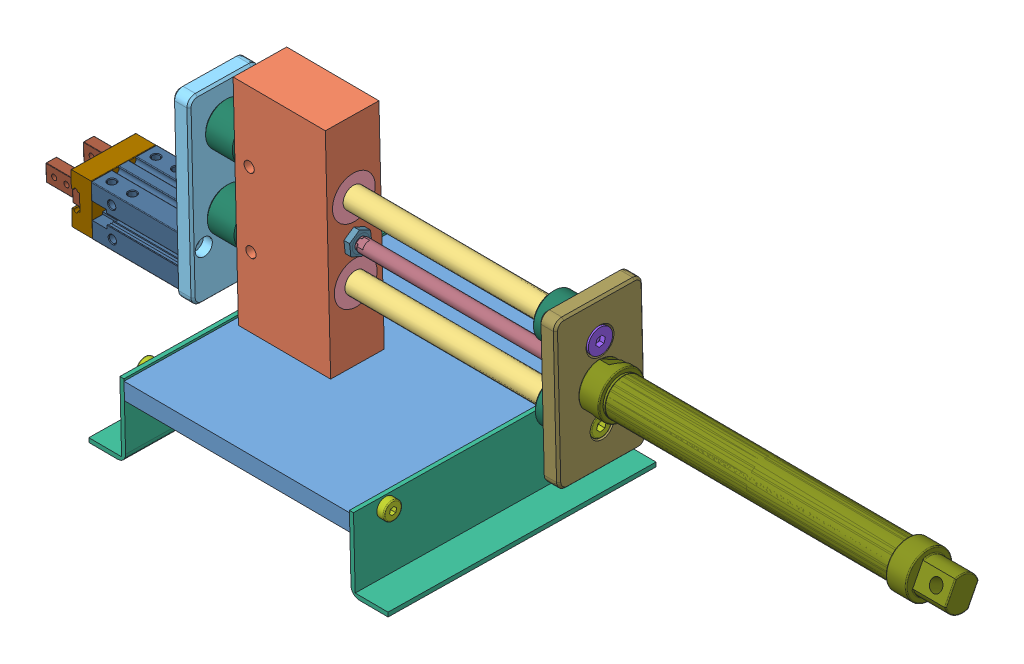
SolidWorks assembly cum s3, configuration Default. Lengths in mm.
Overall size (436.61 137.7 128.52).
35 component instances, 17 part files, 73 mates.
Components (placement in the parent):
- tam de lon-1: tam de lon [Default] at (119.0958 51.1975 54.0073) x (-0.999587 -0.017639 -0.022689) z (-0.022562 -0.007384 0.999718) size (110 8 125)
- con truot s1-2: con truot s1 [Default] at (88.5768 136.6703 53.9498) x (0.999587 0.017639 0.022689) z (0.022562 0.007384 -0.999718) size (45 102 25)
- chot dan huong-1: chot dan huong [Default] at (48.5237 118.4612 52.9114) x (0.021471 -0.983136 -0.181614) z (-0.019103 -0.182026 0.983108) size (10 175 10)
- chot dan huong-2: chot dan huong [Default] at (49.1468 83.4676 52.667) x (0.026236 -0.237789 -0.970963) z (0.011731 -0.971157 0.238153) size (10 175 10)
- bac lot-1: bac lot [Default] at (66.3976 118.7766 53.3171) x (0.028076 -0.767933 -0.639915) z (-0.006137 -0.640287 0.768111) size (20 12 20)
- bac lot-2: bac lot [Default] at (67.0207 83.783 53.0727) x (0.018145 -0.999587 -0.022287) z (-0.022287 -0.022689 0.999494) size (20 12 20)
- bac lot-3: bac lot [Default] at (111.379 119.5704 54.3381) x (-0.014484 -0.372719 0.927831) z (0.024823 -0.927776 -0.37231) size (20 12 20)
- bac lot-4: bac lot [Default] at (112.0021 84.5768 54.0937) x (-0.014484 -0.372719 0.927831) z (0.024823 -0.927776 -0.37231) size (20 12 20)
- ban canh truoc-1: ban canh truoc [Default] at (48.9776 92.9659 52.7333) x (-0.022562 -0.007384 0.999718) z (0.017801 -0.999817 -0.006983) size (33 8 86)
- khoi do-1: khoi do [Default] at (173.7917 36.5109 117.6508) x (0.022562 0.007384 -0.999718) z (-0.999587 -0.017639 -0.022689) size (125 35 18)
- khoi do-2: khoi do [Default] at (64.9414 35.4633 -9.8487) x (-0.022562 -0.007384 0.999718) z (0.999587 0.017639 0.022689) size (125 35 18)
- socket head thin cap screw_din-2: socket head thin cap screw_din [DIN 7984 - M5 x 12 --- 9.6N] at (57.6203 45.7804 100.0932) x (0.999587 0.017639 0.022689) z (-0.022689 -0.0002 0.999743) size (15.5 8.5 8.5)
- socket head thin cap screw_din-3: socket head thin cap screw_din [DIN 7984 - M5 x 12 --- 9.6N] at (59.7637 46.4818 5.12) x (0.999587 0.017639 0.022689) z (-0.022689 -0.0002 0.999743) size (15.5 8.5 8.5)
- socket head thin cap screw_din-4: socket head thin cap screw_din [DIN 7984 - M5 x 12 --- 9.6N] at (180.7137 48.6161 7.8654) x (-0.999587 -0.017639 -0.022689) z (0.022689 -0.968916 -0.246346) size (15.5 8.5 8.5)
- socket head thin cap screw_din-5: socket head thin cap screw_din [DIN 7984 - M5 x 12 --- 9.6N] at (178.5703 47.9147 102.8386) x (-0.999587 -0.017639 -0.022689) z (0.022689 -0.968916 -0.246346) size (15.5 8.5 8.5)
- socket head thin cap screw_din-6: socket head thin cap screw_din [DIN 7984 - M5 x 12 --- 9.6N] at (108.0343 45.1492 61.2151) x (-0.017801 0.999817 0.006983) z (-0.006983 -0.007108 0.99995) size (15.5 8.5 8.5)
- socket head thin cap screw_din-7: socket head thin cap screw_din [DIN 7984 - M5 x 12 --- 9.6N] at (72.3876 44.6249 45.4025) x (-0.017801 0.999817 0.006983) z (-0.006983 -0.007108 0.99995) size (15.5 8.5 8.5)
- socket head thin cap screw_din-10: socket head thin cap screw_din [DIN 7984 - M6 x 14 --- 11N] at (41.35 83.33 52.49) x (0.999587 0.017639 0.022689) z (-0.022689 -0.0002 0.999743) size (18 10 10)
- socket csink head cap screw 10642_din-2: socket csink head cap screw 10642_din [EN ISO 10642 - M6 x 16 - 16N] at (40.3071 118.3162 52.7248) x (0.999587 0.017639 0.022689) z (-0.022678 -0.000819 0.999742) size (16 11.34 11.34)
- NMHZ2-16D-1: NMHZ2-16D [Default] at (57.0123 62.7023 30.2779) x (-0.022562 -0.007384 0.999718) z (-0.999587 -0.017639 -0.022689) size (30.6 23.6 52.5)
  - NMHZ2-16D Slipway-1: NMHZ2-16D Slipway [Default] at (22.4069 2.6078 57.488) size (30.1 23.6 10)
  - NMHZ2-16D cylinder-2: NMHZ2-16D cylinder [Default] at (22.4069 2.6078 14.988) size (30.6 23.6 42.5)
- NMHZ2-16D air claw-1: NMHZ2-16D air claw [Default] at (-9.0173 63.9837 51.9473) x (-0.022562 -0.007384 0.999718) z (-0.999587 -0.017639 -0.022689) size (12 10 21)
- NMHZ2-16D air claw-2: NMHZ2-16D air claw [Default] at (-8.9618 64.0018 49.49) x (0.022562 0.007384 -0.999718) z (-0.999587 -0.017639 -0.022689) size (12 10 21)
- ban canh sau-1: ban canh sau [Default] at (223.763 104.0512 56.7598) x (-0.022562 -0.007384 0.999718) z (-0.017801 0.999817 0.006983) size (41 8 70)
- socket head thin cap screw_din-11: socket head thin cap screw_din [DIN 7984 - M6 x 14 --- 11N] at (231.8713 86.692 56.8146) x (-0.999587 -0.017639 -0.022689) z (0.022689 -0.968916 -0.246346) size (18 10 10)
- socket csink head cap screw 10642_din-6: socket csink head cap screw 10642_din [EN ISO 10642 - M6 x 16 - 16N] at (231.668 121.693 57.0685) x (-0.999587 -0.017639 -0.022689) z (0.022777 -0.96767 -0.251187) size (16 11.34 11.34)
- Part1-1: Part1 [Default] at (260.6534 104.7022 57.5972) x (0.027343 -0.826758 -0.561893) z (0.008847 0.562281 -0.826899) size (6.2 165 6.2)
- Part2-1: Part2 [Default] at (113.19 102.1 54.2499) x (0.02801 -0.421298 -0.90649) z (-0.00643 0.906751 -0.421618) size (11.32 3 9.8)
- bac chan-1: bac chan [Default] at (48.5237 118.4612 52.9114) x (-0.000114 0.791927 -0.610616) z (0.028739 -0.610361 -0.791602) size (20 15 20)
- bac chan-2: bac chan [Default] at (49.1468 83.4676 52.667) x (0.014063 0.388293 -0.921429) z (0.025063 -0.921367 -0.387885) size (20 15 20)
- bac chan-3: bac chan [Default] at (208.4576 121.2834 56.5416) x (0.028616 -0.683831 -0.729079) z (-0.002656 -0.729428 0.684053) size (20 15 20)
- bac chan-4: bac chan [Default] at (209.0807 86.2898 56.2973) x (-0.005838 -0.648408 0.76127) z (-0.02814 0.761088 0.648038) size (20 15 20)
- 16 X 100 Cylinder bore-1: 16 X 100 Cylinder bore [Default] at (311.9265 105.6069 58.761) x (0.028286 -0.464271 -0.885241) z (0.999587 0.017639 0.022689) size (21.5 21.5 192)
- hex thin nut chamfered gradeab_din-2: hex thin nut chamfered gradeab_din [Hexagon Thin Nut ISO 4035 - M8 - N] at (219.7646 103.9806 56.669) x (0.019005 -0.997928 -0.061469) z (-0.999587 -0.017639 -0.022689) size (13 15.01 4)
Mates (geometry in assembly coordinates):
- Parallel5: parallel anti-aligned: plane of tam de lon-1 through (119.0958 51.1975 54.0073) normal (-0.017801 0.999817 0.006983); plane of con truot s1-2 through (90.1077 50.686 53.3493) normal (0.017801 -0.999817 -0.006983)
- Parallel6: parallel anti-aligned: plane of tam de lon-1 through (172.8053 43.7076 117.6817) normal (-0.022562 -0.007384 0.999718); plane of con truot s1-2 through (67.6142 66.3785 40.454) normal (0.022562 0.007384 -0.999718)
- Concentric3: concentric aligned: cylinder of tam de lon-1 through (72.2844 50.4239 45.443) axis (0.017801 -0.999817 -0.006983) radius 2.75; circle of con truot s1-2
- Coincident1: coincident anti-aligned: plane of tam de lon-1 through (119.0958 51.1975 54.0073) normal (-0.017801 0.999817 0.006983); plane of con truot s1-2 through (90.1077 50.686 53.3493) normal (0.017801 -0.999817 -0.006983)
- Concentric4: concentric anti-aligned: cylinder of con truot s1-2 through (41.408 118.3356 52.7498) axis (0.999587 0.017639 0.022689) radius 6; cylinder of chot dan huong-1 through (321.411 123.2766 59.1055) axis (-0.999587 -0.017639 -0.022689) radius 5
- Concentric5: concentric anti-aligned: cylinder of con truot s1-2 through (42.031 83.342 52.5054) axis (0.999587 0.017639 0.022689) radius 6; cylinder of chot dan huong-2 through (322.034 88.283 58.8611) axis (-0.999587 -0.017639 -0.022689) radius 5
- Concentric6: concentric anti-aligned: cylinder of con truot s1-2 through (41.408 118.3356 52.7498) axis (0.999587 0.017639 0.022689) radius 6; cylinder of bac lot-1 through (78.3927 118.9883 53.5893) axis (-0.999587 -0.017639 -0.022689) radius 6
- Coincident2: coincident anti-aligned: plane of con truot s1-2 through (68.3968 118.8119 53.3624) normal (-0.999587 -0.017639 -0.022689); plane of bac lot-1 through (68.3968 118.8119 53.3624) normal (0.999587 0.017639 0.022689)
- Concentric7: concentric anti-aligned: cylinder of con truot s1-2 through (42.031 83.342 52.5054) axis (0.999587 0.017639 0.022689) radius 6; cylinder of bac lot-2 through (79.0157 83.9947 53.3449) axis (-0.999587 -0.017639 -0.022689) radius 6
- Coincident3: coincident anti-aligned: plane of con truot s1-2 through (69.0199 83.8183 53.1181) normal (-0.999587 -0.017639 -0.022689); plane of bac lot-2 through (69.0199 83.8183 53.1181) normal (0.999587 0.017639 0.022689)
- Concentric8: concentric aligned: cylinder of con truot s1-2 through (41.408 118.3356 52.7498) axis (0.999587 0.017639 0.022689) radius 6; cylinder of bac lot-3 through (99.384 119.3587 54.0658) axis (0.999587 0.017639 0.022689) radius 6
- Coincident4: coincident anti-aligned: plane of con truot s1-2 through (109.3799 119.5351 54.2927) normal (0.999587 0.017639 0.022689); plane of bac lot-3 through (109.3799 119.5351 54.2927) normal (-0.999587 -0.017639 -0.022689)
- Concentric9: concentric aligned: cylinder of con truot s1-2 through (42.031 83.342 52.5054) axis (0.999587 0.017639 0.022689) radius 6; cylinder of bac lot-4 through (100.0071 84.3651 53.8214) axis (0.999587 0.017639 0.022689) radius 6
- Coincident5: coincident anti-aligned: plane of con truot s1-2 through (110.0029 84.5415 54.0483) normal (0.999587 0.017639 0.022689); plane of bac lot-4 through (110.0029 84.5415 54.0483) normal (-0.999587 -0.017639 -0.022689)
- Concentric10: concentric aligned: cylinder of chot dan huong-1 through (321.411 123.2766 59.1055) axis (-0.999587 -0.017639 -0.022689) radius 5; cylinder of ban canh truoc-1 through (48.5237 118.4612 52.9114) axis (-0.999587 -0.017639 -0.022689) radius 3.3
- Concentric11: concentric aligned: cylinder of chot dan huong-2 through (322.034 88.283 58.8611) axis (-0.999587 -0.017639 -0.022689) radius 5; cylinder of ban canh truoc-1 through (49.1468 83.4676 52.667) axis (-0.999587 -0.017639 -0.022689) radius 3.3
- Coincident6: coincident anti-aligned: plane of chot dan huong-1 through (48.5237 118.4612 52.9114) normal (-0.999587 -0.017639 -0.022689); plane of ban canh truoc-1 through (48.9776 92.9659 52.7333) normal (0.999587 0.017639 0.022689)
- Coincident7: coincident anti-aligned: plane of chot dan huong-2 through (49.1468 83.4676 52.667) normal (-0.999587 -0.017639 -0.022689); plane of ban canh truoc-1 through (48.9776 92.9659 52.7333) normal (0.999587 0.017639 0.022689)
- Parallel7: parallel aligned: plane of tam de lon-1 through (65.671 42.6903 -9.7789) normal (-0.999587 -0.017639 -0.022689); plane of khoi do-1 through (176.0884 18.6354 -7.4646) normal (-0.999587 -0.017639 -0.022689)
- Parallel8: parallel aligned: plane of tam de lon-1 through (119.0958 51.1975 54.0073) normal (-0.017801 0.999817 0.006983); plane of khoi do-1 through (175.4654 53.629 -7.2202) normal (-0.017801 0.999817 0.006983)
- Concentric14: concentric aligned: cylinder of tam de lon-1 through (160.2221 48.2545 7.4003) axis (0.999587 0.017639 0.022689) radius 2.5; cylinder of khoi do-1 through (52.2667 46.3495 4.9498) axis (0.999587 0.017639 0.022689) radius 2.5
- Coincident10: coincident anti-aligned: plane of tam de lon-1 through (175.6256 44.6306 -7.2831) normal (0.999587 0.017639 0.022689); plane of khoi do-1 through (176.0884 18.6354 -7.4646) normal (-0.999587 -0.017639 -0.022689)
- Parallel9: parallel anti-aligned: plane of tam de lon-1 through (65.671 42.6903 -9.7789) normal (-0.999587 -0.017639 -0.022689); plane of khoi do-2 through (63.3136 15.7721 115.0043) normal (0.999587 0.017639 0.022689)
- Parallel10: parallel anti-aligned: plane of tam de lon-1 through (119.0958 51.1975 54.0073) normal (-0.017801 0.999817 0.006983); plane of khoi do-2 through (63.3136 15.7721 115.0043) normal (0.017801 -0.999817 -0.006983)
- Concentric15: concentric aligned: cylinder of tam de lon-1 through (80.2552 46.8434 5.5851) axis (-0.999587 -0.017639 -0.022689) radius 2.5; cylinder of khoi do-2 through (188.2106 48.7484 8.0356) axis (-0.999587 -0.017639 -0.022689) radius 2.5
- Coincident11: coincident anti-aligned: plane of tam de lon-1 through (65.671 42.6903 -9.7789) normal (-0.999587 -0.017639 -0.022689); plane of khoi do-2 through (63.3136 15.7721 115.0043) normal (0.999587 0.017639 0.022689)
- Concentric16: concentric aligned: cylinder of khoi do-2 through (186.0672 48.047 103.0088) axis (-0.999587 -0.017639 -0.022689) radius 2.5; cylinder of socket head thin cap screw_din-2 through (25.8834 45.2204 99.3728) axis (-0.999587 -0.017639 -0.022689) radius 4.25
- Coincident12: coincident anti-aligned: plane of khoi do-2 through (61.2788 17.7365 114.9729) normal (-0.999587 -0.017639 -0.022689); plane of socket head thin cap screw_din-2 through (61.0438 50.0915 100.1718) normal (0.999587 0.017639 0.022689)
- Concentric17: concentric aligned: cylinder of khoi do-2 through (188.2106 48.7484 8.0356) axis (-0.999587 -0.017639 -0.022689) radius 2.5; cylinder of socket head thin cap screw_din-3 through (28.0268 45.9218 4.3996) axis (-0.999587 -0.017639 -0.022689) radius 4.25
- Coincident13: coincident anti-aligned: plane of khoi do-2 through (61.2788 17.7365 114.9729) normal (-0.999587 -0.017639 -0.022689); plane of socket head thin cap screw_din-3 through (63.1872 50.7929 5.1986) normal (0.999587 0.017639 0.022689)
- Concentric18: concentric aligned: cylinder of khoi do-1 through (52.2667 46.3495 4.9498) axis (0.999587 0.017639 0.022689) radius 2.5; cylinder of socket head thin cap screw_din-4 through (212.4506 49.1762 8.5858) axis (0.999587 0.017639 0.022689) radius 4.25
- Coincident14: coincident anti-aligned: plane of khoi do-1 through (178.052 20.6703 -7.4053) normal (0.999587 0.017639 0.022689); plane of socket head thin cap screw_din-4 through (177.2901 49.6031 3.6681) normal (-0.999587 -0.017639 -0.022689)
- Concentric19: concentric aligned: cylinder of khoi do-1 through (50.1234 45.6481 99.9231) axis (0.999587 0.017639 0.022689) radius 2.5; cylinder of socket head thin cap screw_din-5 through (210.3072 48.4747 103.559) axis (0.999587 0.017639 0.022689) radius 4.25
- Coincident15: coincident anti-aligned: plane of khoi do-1 through (178.052 20.6703 -7.4053) normal (0.999587 0.017639 0.022689); plane of socket head thin cap screw_din-5 through (175.1467 48.9017 98.6413) normal (-0.999587 -0.017639 -0.022689)
- Concentric20: concentric aligned: cylinder of tam de lon-1 through (107.972 48.6485 61.2395) axis (0.017801 -0.999817 -0.006983) radius 5; cylinder of socket head thin cap screw_din-6 through (108.5995 13.405 60.9934) axis (0.017801 -0.999817 -0.006983) radius 4.25
- Coincident16: coincident anti-aligned: plane of tam de lon-1 through (107.972 48.6485 61.2395) normal (0.017801 -0.999817 -0.006983); plane of socket head thin cap screw_din-6 through (103.7228 48.5731 61.2093) normal (-0.017801 0.999817 0.006983)
- Concentric21: concentric aligned: cylinder of tam de lon-1 through (72.2844 50.4239 45.443) axis (0.017801 -0.999817 -0.006983) radius 2.75; cylinder of socket head thin cap screw_din-7 through (72.9528 12.8807 45.1808) axis (0.017801 -0.999817 -0.006983) radius 4.25
- Coincident17: coincident anti-aligned: plane of tam de lon-1 through (72.3253 48.1243 45.4269) normal (0.017801 -0.999817 -0.006983); plane of socket head thin cap screw_din-7 through (68.0761 48.0489 45.3967) normal (-0.017801 0.999817 0.006983)
- Concentric23: concentric aligned: cylinder of ban canh truoc-1 through (45.3483 83.4006 52.5807) axis (-0.999587 -0.017639 -0.022689) radius 5.5; cylinder of socket head thin cap screw_din-10 through (9.6131 82.77 51.7696) axis (-0.999587 -0.017639 -0.022689) radius 5
- Coincident19: coincident anti-aligned: plane of ban canh truoc-1 through (45.3483 83.4006 52.5807) normal (-0.999587 -0.017639 -0.022689); plane of socket head thin cap screw_din-10 through (45.2601 88.3998 52.5797) normal (0.999587 0.017639 0.022689)
- Coincident20: coincident aligned: cone of ban canh truoc-1 through (43.7257 118.3765 52.8024) axis (0.999587 0.017639 0.022689); cone of socket csink head cap screw 10642_din-2 through (41.3567 118.3347 52.7487) axis (0.999587 0.017639 0.022689)
- Concentric24: concentric anti-aligned: cylinder of ban canh truoc-1 through (49.0908 72.5884 63.5884) axis (-0.999587 -0.017639 -0.022689) radius 2.25; cylinder of NMHZ2-16D-1/NMHZ2-16D cylinder-2 through (26.1003 72.1827 63.0666) axis (0.999587 0.017639 0.022689) radius 2
- Concentric25: concentric aligned: cylinder of ban canh truoc-1 through (45.456 57.6759 41.3901) axis (0.999587 0.017639 0.022689) radius 4; cylinder of NMHZ2-16D-1/NMHZ2-16D cylinder-2 through (26.8637 57.3478 40.9681) axis (0.999587 0.017639 0.022689) radius 2
- Coincident22: coincident anti-aligned: plane of ban canh truoc-1 through (40.981 92.8248 52.5518) normal (-0.999587 -0.017639 -0.022689); plane of NMHZ2-16D-1/NMHZ2-16D cylinder-2 through (41.4785 64.8799 52.3566) normal (0.999587 0.017639 0.022689)
- Parallel11: parallel anti-aligned: plane of NMHZ2-16D-1/NMHZ2-16D Slipway-1 through (-6.4938 64.1905 28.7625) normal (-0.999587 -0.017639 -0.022689); plane of NMHZ2-16D air claw-1 through (-7.2888 63.9303 63.9893) normal (0.999587 0.017639 0.022689)
- Concentric26: concentric anti-aligned: cylinder of NMHZ2-16D-1/NMHZ2-16D Slipway-1 through (-8.5642 68.1545 28.7451) axis (-0.022562 -0.007384 0.999718) radius 1; cylinder of NMHZ2-16D air claw-1 through (-9.3592 67.8943 63.9719) axis (0.022562 0.007384 -0.999718) radius 1
- Parallel12: parallel anti-aligned: plane of NMHZ2-16D-1/NMHZ2-16D Slipway-1 through (-6.4938 64.1905 28.7625) normal (-0.999587 -0.017639 -0.022689); plane of NMHZ2-16D air claw-2 through (-6.6919 64.1257 37.5387) normal (0.999587 0.017639 0.022689)
- Concentric27: concentric aligned: cylinder of NMHZ2-16D-1/NMHZ2-16D Slipway-1 through (-8.4218 60.156 28.6892) axis (-0.022562 -0.007384 0.999718) radius 1; cylinder of NMHZ2-16D air claw-2 through (-8.6199 60.0911 37.4654) axis (-0.022562 -0.007384 0.999718) radius 1
- Concentric28: concentric anti-aligned: cylinder of chot dan huong-1 through (321.411 123.2766 59.1055) axis (-0.999587 -0.017639 -0.022689) radius 5; cylinder of ban canh sau-1 through (223.4514 121.548 56.882) axis (0.999587 0.017639 0.022689) radius 3.3
- Concentric29: concentric anti-aligned: cylinder of chot dan huong-2 through (322.034 88.283 58.8611) axis (-0.999587 -0.017639 -0.022689) radius 5; cylinder of ban canh sau-1 through (224.0745 86.5544 56.6376) axis (0.999587 0.017639 0.022689) radius 3.3
- Coincident23: coincident anti-aligned: plane of chot dan huong-1 through (223.4514 121.548 56.882) normal (0.999587 0.017639 0.022689); plane of ban canh sau-1 through (223.763 104.0512 56.7598) normal (-0.999587 -0.017639 -0.022689)
- Coincident24: coincident anti-aligned: plane of chot dan huong-2 through (224.0745 86.5544 56.6376) normal (0.999587 0.017639 0.022689); plane of ban canh sau-1 through (223.763 104.0512 56.7598) normal (-0.999587 -0.017639 -0.022689)
- Concentric301: concentric aligned: cylinder of ban canh sau-1 through (224.0745 86.5544 56.6376) axis (0.999587 0.017639 0.022689) radius 3.3; cylinder of socket head thin cap screw_din-11 through (263.6081 87.252 57.535) axis (0.999587 0.017639 0.022689) radius 5
- Coincident251: coincident anti-aligned: plane of ban canh sau-1 through (227.8729 86.6214 56.7238) normal (0.999587 0.017639 0.022689); plane of socket head thin cap screw_din-11 through (227.9611 87.8552 51.8792) normal (-0.999587 -0.017639 -0.022689)
- Coincident26: coincident aligned: cone of ban canh sau-1 through (228.2494 121.6327 56.9909) axis (-0.999587 -0.017639 -0.022689); cone of socket csink head cap screw 10642_din-6 through (230.6185 121.6745 57.0447) axis (-0.999587 -0.017639 -0.022689)
- Concentric32: concentric aligned: cylinder of Part1-1 through (114.7137 102.1269 54.2845) axis (0.999587 0.017639 0.022689) radius 2.6; cylinder of Part2-1 through (114.6893 102.1265 54.284) axis (0.999587 0.017639 0.022689) radius 2.75
- Concentric33: concentric aligned: cylinder of con truot s1-2 through (96.6968 101.809 53.8756) axis (0.999587 0.017639 0.022689) radius 2.5; cylinder of Part1-1 through (114.7137 102.1269 54.2845) axis (0.999587 0.017639 0.022689) radius 2.6
- Lock1: lock: unknown of Part1-1; unknown of Part2-1
- Coincident27: coincident anti-aligned: plane of con truot s1-2 through (112.0316 66.9877 66.468) normal (0.999587 0.017639 0.022689); plane of Part2-1 through (111.6906 102.0736 54.2159) normal (-0.999587 -0.017639 -0.022689)
- Concentric37: concentric anti-aligned: cylinder of chot dan huong-1 through (321.411 123.2766 59.1055) axis (-0.999587 -0.017639 -0.022689) radius 5; cylinder of bac chan-1 through (48.5237 118.4612 52.9114) axis (0.999587 0.017639 0.022689) radius 5
- Coincident31: coincident anti-aligned: plane of ban canh truoc-1 through (48.9776 92.9659 52.7333) normal (0.999587 0.017639 0.022689); plane of bac chan-1 through (48.5237 118.4612 52.9114) normal (-0.999587 -0.017639 -0.022689)
- Concentric38: concentric anti-aligned: cylinder of chot dan huong-2 through (322.034 88.283 58.8611) axis (-0.999587 -0.017639 -0.022689) radius 5; cylinder of bac chan-2 through (49.1468 83.4676 52.667) axis (0.999587 0.017639 0.022689) radius 5
- Coincident32: coincident anti-aligned: plane of ban canh truoc-1 through (48.9776 92.9659 52.7333) normal (0.999587 0.017639 0.022689); plane of bac chan-2 through (49.1468 83.4676 52.667) normal (-0.999587 -0.017639 -0.022689)
- Concentric391: concentric aligned: cylinder of chot dan huong-1 through (321.411 123.2766 59.1055) axis (-0.999587 -0.017639 -0.022689) radius 5; cylinder of bac chan-3 through (223.4514 121.548 56.882) axis (-0.999587 -0.017639 -0.022689) radius 10
- Coincident33: coincident anti-aligned: plane of ban canh sau-1 through (223.763 104.0512 56.7598) normal (-0.999587 -0.017639 -0.022689); plane of bac chan-3 through (223.4514 121.548 56.882) normal (0.999587 0.017639 0.022689)
- Concentric401: concentric aligned: cylinder of chot dan huong-2 through (322.034 88.283 58.8611) axis (-0.999587 -0.017639 -0.022689) radius 5; cylinder of bac chan-4 through (224.0745 86.5544 56.6376) axis (-0.999587 -0.017639 -0.022689) radius 10
- Coincident34: coincident anti-aligned: plane of ban canh sau-1 through (223.763 104.0512 56.7598) normal (-0.999587 -0.017639 -0.022689); plane of bac chan-4 through (224.0745 86.5544 56.6376) normal (0.999587 0.017639 0.022689)
- LimitDistance2: limit distance = 2.8813 mm anti-aligned: plane of bac chan-1 through (63.5175 118.7258 53.2517) normal (0.999587 0.017639 0.022689); plane of con truot s1-2 through (67.0502 66.1939 65.447) normal (-0.999587 -0.017639 -0.022689)
- Concentric402: concentric anti-aligned: cylinder of Part1-1 through (95.7216 101.7918 53.8534) axis (0.999587 0.017639 0.022689) radius 3.1; cylinder of 16 X 100 Cylinder bore-1 through (390.8939 107.0004 60.5534) axis (-0.999587 -0.017639 -0.022689) radius 3.25
- LimitDistance4: limit distance = 121.2943 mm anti-aligned: plane of Part1-1 through (260.6534 104.7022 57.5972) normal (0.999587 0.017639 0.022689); plane of 16 X 100 Cylinder bore-1 through (381.8976 106.8417 60.3492) normal (-0.999587 -0.017639 -0.022689)
- Coincident252: coincident anti-aligned: plane of ban canh sau-1 through (227.7613 104.1217 56.8505) normal (0.999587 0.017639 0.022689); plane of 16 X 100 Cylinder bore-1 through (227.7613 104.1217 56.8505) normal (-0.999587 -0.017639 -0.022689)
- Concentric403: concentric aligned: cylinder of 16 X 100 Cylinder bore-1 through (258.3449 104.6614 57.5448) axis (-0.999587 -0.017639 -0.022689) radius 5.1; cylinder of hex thin nut chamfered gradeab_din-2 through (244.7918 104.4223 57.2371) axis (-0.999587 -0.017639 -0.022689) radius 4
- Coincident253: coincident anti-aligned: plane of ban canh sau-1 through (223.763 104.0512 56.7598) normal (-0.999587 -0.017639 -0.022689); plane of hex thin nut chamfered gradeab_din-2 through (223.6011 103.5868 64.2492) normal (0.999587 0.017639 0.022689)
